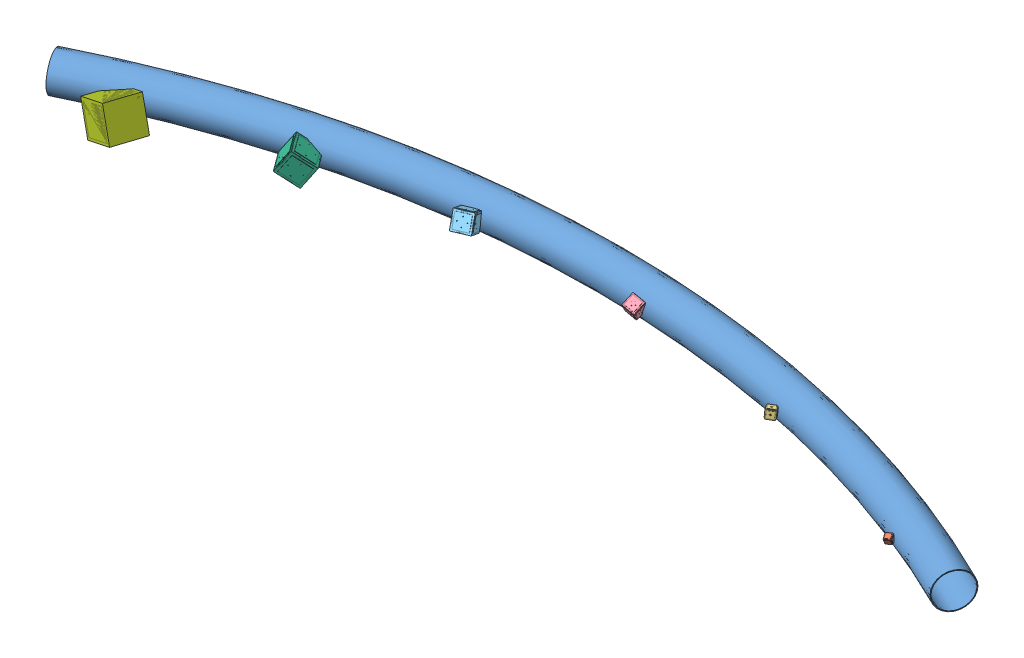
SolidWorks assembly tube2A, configuration Default. Lengths in mm.
Overall size (5548.73 212.13 5064.2).
7 component instances, 7 part files, 0 mates.
Components (placement in the parent):
- tubes-1: tubes [tube2A] at origin size (5548.73 168.28 5064.2)
- cube_15-2: cube_15 [Default] at (1757.1943 7.1888 -324.7748) x (0.466813 -0.378836 0.799105) z (-0.87943 -0.103618 0.464614) size (31.12 31.12 31.12)
- cube_16-2: cube_16 [Default] at (968.8015 9.4519 -559.7177) x (0.806784 -0.069825 -0.586706) z (0.590423 0.132849 0.796085) size (41.27 41.27 42.23)
- cube_17-2: cube_17 [Default] at (219.4124 11.792 -668.2944) x (0.954748 -0.289413 -0.068523) z (-0.098768 -0.525851 0.844823) size (59.24 59.06 59.06)
- cube_18-2: cube_18 [Default] at (-522.2233 15.3473 -617.0525) x (0.916882 -0.004667 -0.399132) z (0.359767 0.442803 0.821276) size (81.92 81.92 84.87)
- cube_19-2: cube_19 [Default] at (-1183.1884 -5.1426 -489.4193) x (0.660298 -0.557655 -0.503018) z (0.583277 -0.041114 0.811232) size (112.39 112.39 112.56)
- cube_20-2: cube_20 [Default] at (-1812.0839 -23.6863 -257.1651) x (-0.350316 0.927365 -0.131426) z (-0.262185 0.037617 0.964284) size (157.73 157.73 159.27)
